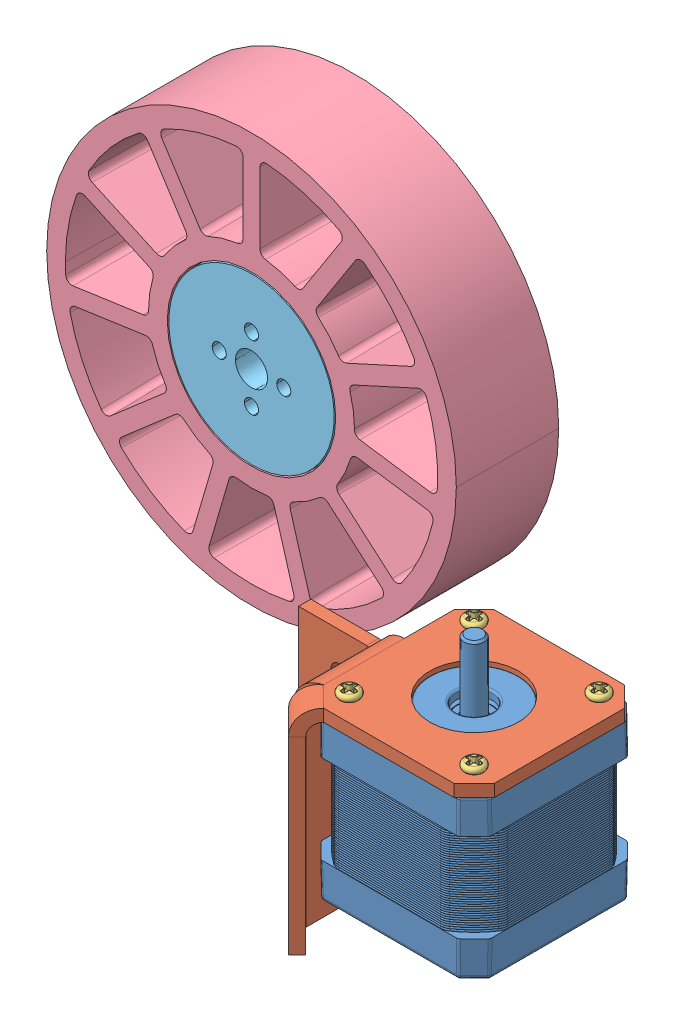
SolidWorks assembly Assem1, configuration Default. Lengths in mm.
Overall size (190.81 101.6 114.77).
9 component instances, 5 part files, 11 mates.
Components (placement in the parent):
- Nema 17 Stepper Motor-1: Nema 17 Stepper Motor [Default] at (-5.7555 12.998 57.6778) size (42 55.5 48)
- Stepper Motor Mount 2020E-1: Stepper Motor Mount 2020E [Default] at (-33.6829 42.998 88.1395) x (0 0 -1) z (0 -1 0) size (46.69 68.51 53.41)
- Screw-1: Screw [Default] at (-21.2555 46.0358 42.1778) size (5 33.46 5)
- Screw-2: Screw [Default] at (-21.2555 46.0358 73.1778) size (5 33.46 5)
- Screw-3: Screw [Default] at (9.7445 46.0358 42.1778) size (5 33.46 5)
- Screw-4: Screw [Default] at (9.7445 46.0358 73.1778) size (5 33.46 5)
- am-3563 4IN 8mm Round Compliant Wheel REV2.STEP-1: am-3563 4IN 8mm Round Compliant Wheel REV2.STEP [Default] at (-157.9927 15.5029 5.4517) size (101.6 101.6 25.74)
  - 4IN Compliant Wheel FINAL Overmold.STEP-1: 4IN Compliant Wheel FINAL Overmold.STEP [Default] at (33.3747 9.5942 -11.4296) size (101.6 101.6 25.74)
  - 2in Wheel Intergrated 8mm Hub.STEP-1: 2in Wheel Intergrated 8mm Hub.STEP [Default] at (33.3747 9.5942 -24.1296) size (41.91 41.91 25.4)
Mates (geometry in assembly coordinates):
- Coincident1: coincident anti-aligned: plane of Nema 17 Stepper Motor-1 through (-5.7555 42.998 57.6778) normal (0 1 0); plane of Stepper Motor Mount 2020E-1 through (-33.6829 42.998 88.1395) normal (0 -1 0)
- Concentric1: concentric aligned: cylinder of Nema 17 Stepper Motor-1 through (-5.7555 59.498 57.6778) axis (0 -1 0) radius 2.5; cylinder of Stepper Motor Mount 2020E-1 through (-5.7555 46.0358 57.6778) axis (0 -1 0) radius 11
- Concentric2: concentric aligned: cylinder of Nema 17 Stepper Motor-1 through (9.7445 44.998 42.1778) axis (0 -1 0) radius 1.5; cylinder of Stepper Motor Mount 2020E-1 through (9.7445 46.0358 42.1778) axis (0 -1 0) radius 1.5
- Coincident2: coincident anti-aligned: plane of Stepper Motor Mount 2020E-1 through (-33.6829 46.0358 88.1395) normal (0 1 0); plane of Screw-1 through (-19.7555 46.0358 42.1778) normal (0 -1 0)
- Concentric4: concentric aligned: cylinder of Stepper Motor Mount 2020E-1 through (-21.2555 46.0358 42.1778) axis (0 -1 0) radius 1.5; cylinder of Screw-1 through (-21.2555 14.5358 42.1778) axis (0 -1 0) radius 1.5
- Coincident6: coincident: plane of Stepper Motor Mount 2020E-1 through (-33.6829 46.0358 88.1395) normal (0 1 0); plane of Screw-2 through (-19.7555 46.0358 73.1778) normal (0 -1 0)
- Concentric5: concentric aligned: cylinder of Stepper Motor Mount 2020E-1 through (-21.2555 46.0358 73.1778) axis (0 -1 0) radius 1.5; cylinder of Screw-2 through (-21.2555 14.5358 73.1778) axis (0 -1 0) radius 1.5
- Coincident7: coincident: plane of Stepper Motor Mount 2020E-1 through (-33.6829 46.0358 88.1395) normal (0 1 0); plane of Screw-4 through (11.2445 46.0358 73.1778) normal (0 -1 0)
- Concentric6: concentric aligned: cylinder of Stepper Motor Mount 2020E-1 through (9.7445 46.0358 73.1778) axis (0 -1 0) radius 1.5; cylinder of Screw-4 through (9.7445 14.5358 73.1778) axis (0 -1 0) radius 1.5
- Coincident8: coincident: plane of Stepper Motor Mount 2020E-1 through (-33.6829 46.0358 88.1395) normal (0 1 0); plane of Screw-3 through (11.2445 46.0358 42.1778) normal (0 -1 0)
- Concentric7: concentric aligned: cylinder of Stepper Motor Mount 2020E-1 through (9.7445 46.0358 42.1778) axis (0 -1 0) radius 1.5; cylinder of Screw-3 through (9.7445 14.5358 42.1778) axis (0 -1 0) radius 1.5
